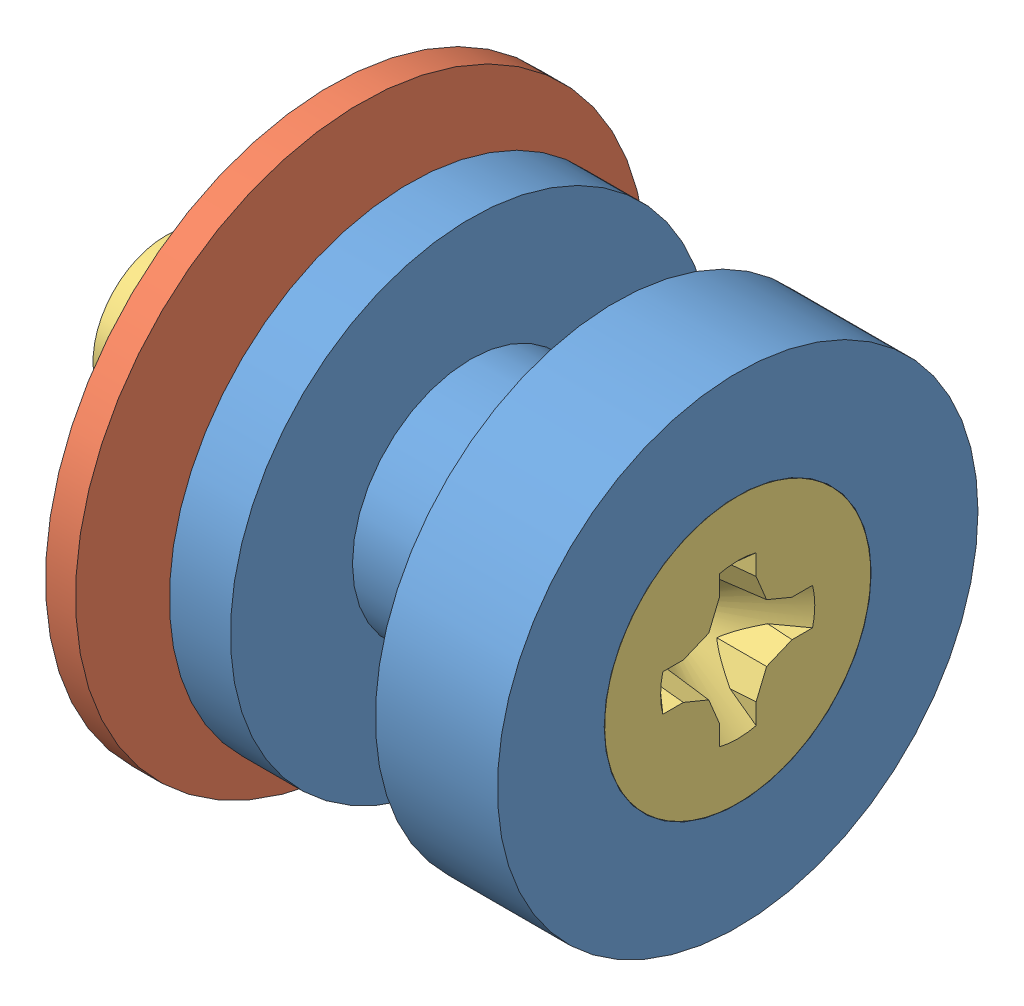
SolidWorks assembly S1A_Railguide, configuration Default. Lengths in mm.
Overall size (19.05 19 19).
3 component instances, 3 part files, 9 mates.
Components (placement in the parent):
- S1A_Railguide_Bolt-1: S1A_Railguide_Bolt [Default] at origin size (10.92 16 16)
- S1A_Welded_Nut_Railguide-1: S1A_Welded_Nut_Railguide [Default] at (-2.6264 0 0) x (0 0 1) z (-1 0 0) size (19 19 11)
- S1A_10-32_Flathead_RailguideScrew-2: S1A_10-32_Flathead_RailguideScrew [91099A365] at (1.397 0 0) x (-1 0 0) z (0 0 -1) size (19.05 8.95 8.95)
Mates (geometry in assembly coordinates):
- Coincident1: coincident aligned: plane of S1A_Railguide_Bolt-1 through (0 0 0) normal (0 0 1)
- Coincident2: coincident aligned: plane of S1A_Railguide_Bolt-1 through (0 0 0) normal (0 1 0)
- Coincident3: coincident aligned: plane of S1A_Railguide_Bolt-1 through (0 0 0) normal (1 0 0)
- Concentric1: concentric aligned: cylinder of S1A_Railguide_Bolt-1 through (0 0 0) axis (1 0 0) radius 3.429; cylinder of S1A_10-32_Flathead_RailguideScrew-2 through (10.922 0 0) axis (1 0 0) radius 2.413
- Coincident4: coincident aligned: plane of S1A_Railguide_Bolt-1 through (10.922 0 0) normal (1 0 0); plane of S1A_10-32_Flathead_RailguideScrew-2 through (10.922 0 0) normal (1 0 0)
- Concentric2: concentric anti-aligned: cylinder of S1A_Welded_Nut_Railguide-1 through (-0.0864 0 0) axis (-1 0 0) radius 2.5; cylinder of S1A_10-32_Flathead_RailguideScrew-2 through (10.922 0 0) axis (1 0 0) radius 2.413
- Parallel1: parallel aligned: plane of S1A_Welded_Nut_Railguide-1 through (-2.6264 0 0) normal (0 0 1)
- Distance1: distance = 1.6256 mm anti-aligned: plane of S1A_Welded_Nut_Railguide-1 through (-1.6256 0 0) normal (1 0 0); plane of S1A_Railguide_Bolt-1 through (0 0 0) normal (-1 0 0)
- Parallel2: parallel aligned: plane of S1A_10-32_Flathead_RailguideScrew-2 through (1.397 0 0) normal (0 1 0)
